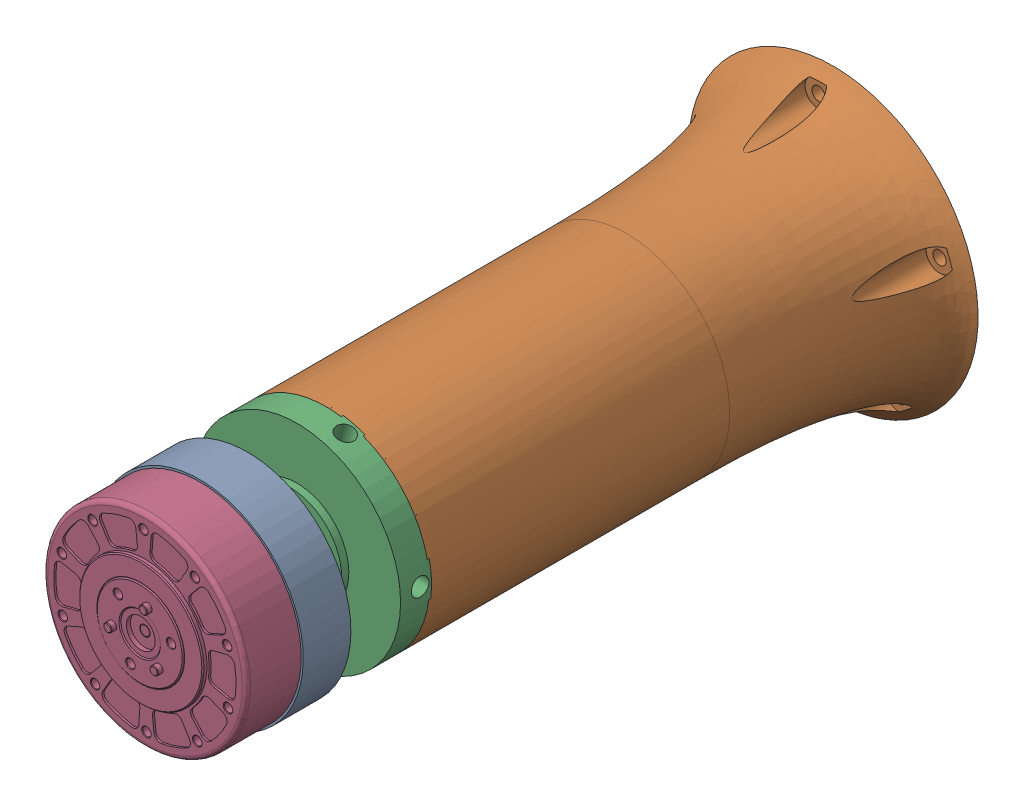
SolidWorks assembly 01-BASE, configuration Default. Lengths in mm.
Overall size (183.52 182.45 337.53).
4 component instances, 4 part files, 0 mates.
Components (placement in the parent):
- Motor_Flange-1: Motor_Flange [Default] at (0 0 306) x (0.34202 -0.939693 0) z (0 0 -1) size (100 100 28.01)
- Base-1: Base [Default] at (0 0 268.5) x (0.34202 -0.939693 0) z (0 0 -1) size (141.87 143.66 255.53)
- Base_Flange-1: Base_Flange [Default] at (0 0 301) x (0.34202 -0.939693 0) z (0 0 -1) size (100.04 100 35.5)
- zz_myactuator_rmd_x8-1: zz_myactuator_rmd_x8 [Default] at (-79.1783 -258.9804 -280.0595) x (0 0 1) z (-0.956305 0.292372 0) size (44.5 98 98)
